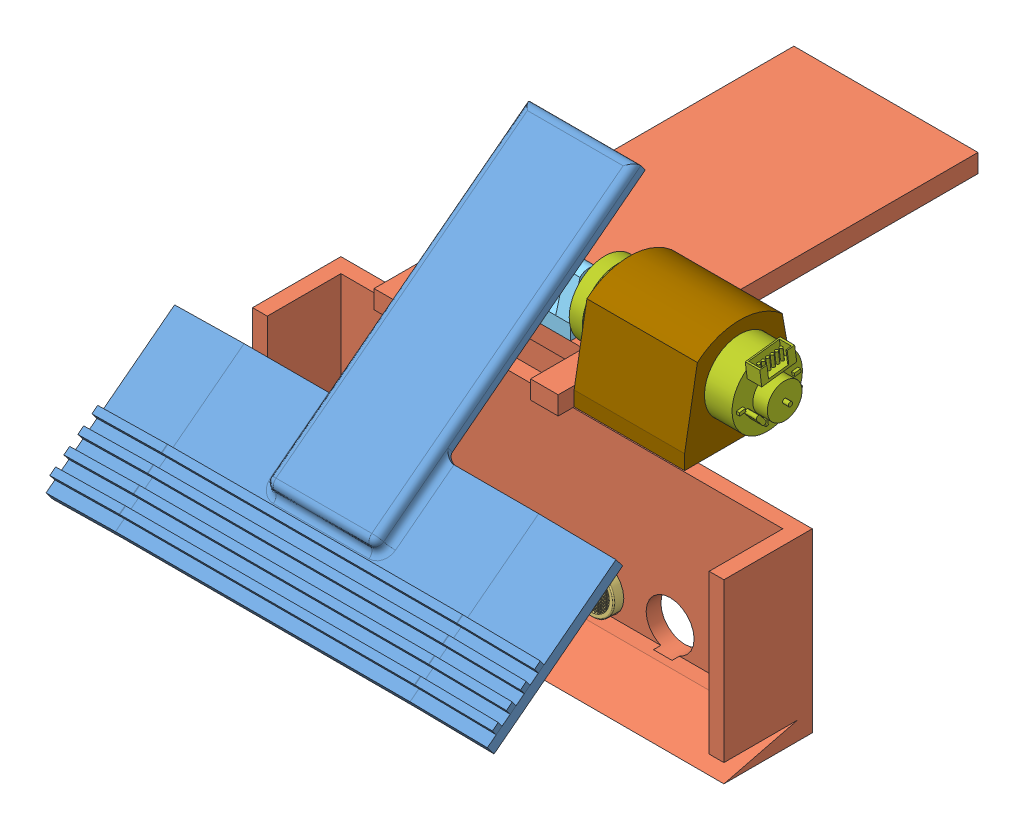
SolidWorks assembly ScoopClawAssembly, configuration Default. Lengths in mm.
Overall size (171.3 138.74 218).
10 component instances, 9 part files, 20 mates.
Components (placement in the parent):
- Scooper-1: Scooper [Default] at (144.6073 0.6103 138.0053) x (1 0 0) z (0 0.793599 0.608442) size (152.65 142.24 11.1)
- Scooper_Base-1: Scooper_Base [Default] at (144.6073 -61.534 72.0438) size (162.56 95.25 144.78)
- HC-SR04-UltrasonicSensor v7-2: HC-SR04-UltrasonicSensor v7 [Default] at (144.5683 -48.834 48.9638) x (-1 0 0) z (0 0 1) size (45.45 26.2 17.79)
- Hinge_Joint-1: Hinge_Joint [Default] at (126.8273 46.416 67.8239) x (0 0.774266 0.63286) z (1 0 0) size (8.89 8.89 40.64)
- Hinge_Part1-1: Hinge_Part1 [Default] at (144.6073 33.716 67.8239) size (35.56 18.62 12.7)
- Hinge_Part2-1: Hinge_Part2 [Default] at (144.6073 54.4789 74.0056) x (1 0 0) z (0 0.608442 -0.793599) size (25.4 16.08 12.7)
- 6V Motor Spin-1: 6V Motor Spin [Default] at (231.6559 14.0419 25.1949) x (-0.072098 -0.103157 0.992049) z (-0.996718 0.044149 -0.067847) size (29.63 28.32 78.39)
  - Motor no spinny boi-1: Motor no spinny boi [Default] at (39.6165 36.3483 7.7453) x (0.997226 -0.015871 -0.072721) z (0.072098 -0.036799 0.996718) size (24.4 25.49 66.9)
  - Motor spinny boi-1: Motor spinny boi [Default] at (39.6165 36.3483 7.7453) x (0.547957 0.836461 -0.008754) z (0.072098 -0.036799 0.996718) size (3.95 3.95 13.05)
- Motor Support-1: Motor Support [Default] at (195.4073 27.366 67.8239) size (38.1 54.53 38.1)
Mates (geometry in assembly coordinates):
- Concentric1: concentric: cylinder of Scooper_Base-1 through (157.6883 -48.834 61.8838) axis (0 0 -1) radius 8.2697; cylinder of HC-SR04-UltrasonicSensor v7-2 through (157.6883 -48.834 50.5638) axis (0 0 1) radius 8
- Coincident1: coincident: plane of Scooper_Base-1 through (144.6073 -61.534 54.2638) normal (0 0 -1); plane of HC-SR04-UltrasonicSensor v7-2 through (144.5683 -56.2197 54.2638) normal (0 0 1)
- Coincident2: coincident: plane of Scooper_Base-1 through (144.6073 33.716 72.0438) normal (0 1 0); plane of Hinge_Part1-1 through (144.6073 33.716 67.8239) normal (0 -1 0)
- Coincident4: coincident: plane of Scooper_Base-1 through (166.8323 -61.535 74.1739) normal (0 0 1); plane of Hinge_Part1-1 through (126.8273 38.796 74.1739) normal (0 0 1)
- Distance1: distance = 4.445 mm: plane of Hinge_Part1-1 through (162.3873 38.796 74.1739) normal (1 0 0); plane of Scooper_Base-1 through (166.8323 -61.535 113.2075) normal (-1 0 0)
- Concentric2: concentric: cylinder of Hinge_Joint-1 through (162.3873 46.416 67.8239) axis (-1 0 0) radius 3.175; cylinder of Hinge_Part1-1 through (126.8273 46.416 67.8239) axis (1 0 0) radius 3.175
- Coincident6: coincident: plane of Hinge_Joint-1 through (126.8273 46.416 67.8239) normal (1 0 0); plane of Hinge_Part1-1 through (126.8273 38.796 74.1739) normal (-1 0 0)
- Concentric3: concentric: cylinder of Hinge_Joint-1 through (162.3873 46.416 67.8239) axis (-1 0 0) radius 3.175; cylinder of Hinge_Part2-1 through (131.9073 46.416 67.8239) axis (1 0 0) radius 3.175
- Coincident7: coincident: plane of Hinge_Part1-1 through (157.3073 48.0002 67.8239) normal (-1 0 0); plane of Hinge_Part2-1 through (157.3073 56.3268 67.4208) normal (1 0 0)
- Coincident8: coincident: plane of Scooper-1 through (144.6073 3.6339 140.3235) normal (0 -0.793599 -0.608442); plane of Hinge_Part2-1 through (144.6073 54.4789 74.0056) normal (0 0.793599 0.608442)
- Distance2: distance = 6.35 mm: plane of Scooper-1 through (163.6573 7.6654 143.4144) normal (1 0 0); plane of Hinge_Part2-1 through (157.3073 56.3268 67.4208) normal (1 0 0)
- LimitDistance1: limit distance = 55.1414 mm: point of Scooper-1; plane of Scooper_Base-1 through (144.6073 -61.534 59.3438) normal (0 0 1)
- Distance4: distance = 59.436 mm: line of Scooper-1 through (163.6573 22.1792 116.1346) axis (-1 0 0); line of Hinge_Part2-1 through (131.9073 58.3425 68.9663) axis (1 0 0)
- LimitDistance2: limit distance = 39.4628 mm: plane of Scooper_Base-1 through (144.6073 33.716 72.0438) normal (0 1 0); line of Scooper-1 through (163.6573 73.1788 49.6152) axis (-1 0 0)
- Coincident13: coincident: plane of Hinge_Joint-1 through (154.7673 47.5967 68.789) normal (0 -0.774266 -0.63286); plane of 6V Motor Spin-1/Motor spinny boi-1 through (164.7673 47.5967 68.789) normal (0 0.774266 0.63286)
- Concentric5: concentric: circle of Hinge_Joint-1; circle of 6V Motor Spin-1/Motor no spinny boi-1
- Coincident14: coincident: plane of Hinge_Joint-1 through (154.7673 46.416 67.8239) normal (1 0 0); plane of 6V Motor Spin-1/Motor spinny boi-1 through (154.7673 46.416 67.8239) normal (-1 0 0)
- Coincident15: coincident: plane of Scooper_Base-1 through (176.3573 -10.734 49.1838) normal (1 0 0); plane of Motor Support-1 through (176.3573 32.446 86.8739) normal (-1 0 0)
- Concentric6: concentric: circle of 6V Motor Spin-1/Motor no spinny boi-1; circle of Motor Support-1
- Distance5: distance = 1.27 mm: plane of ? through (138.0414 -62.804 99.5161) normal (0 -1 0); plane of Scooper_Base-1 through (144.6073 -61.534 72.0438) normal (0 -1 0)
